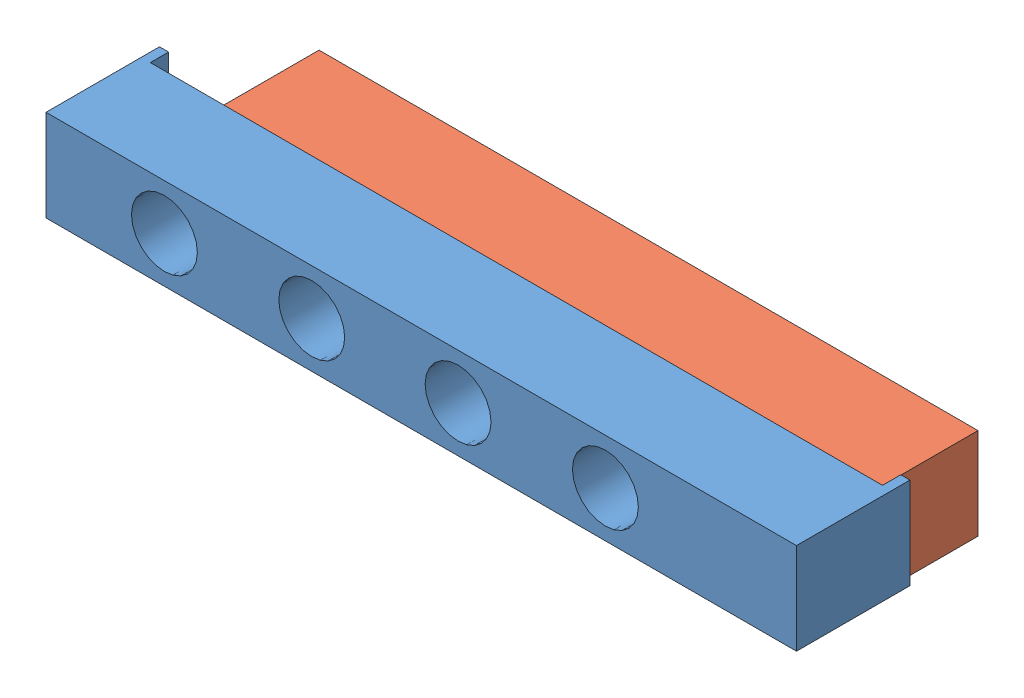
SolidWorks assembly Assembly-release mechanism, configuration Standard. Lengths in mm.
Overall size (205 25 52).
2 component instances, 2 part files, 2 mates.
Components (placement in the parent):
- lower plate-1: lower plate [Standard] at (-123.7143 51.0034 194.5) size (205 25 31)
- upper plate-1: upper plate [Standard] at (-101.1312 51.0034 168.5) size (180 25 26)
Mates (geometry in assembly coordinates):
- Deckungsgleich1: coincident aligned: line of lower plate-1 through (-121.2143 51.0034 194.5) axis (1 0 0); line of upper plate-1 through (-101.1312 51.0034 194.5) axis (1 0 0)
- Deckungsgleich2: coincident aligned: line of lower plate-1 through (78.7857 76.0034 194.5) axis (-1 0 0); line of upper plate-1 through (78.8688 76.0034 194.5) axis (-1 0 0)
